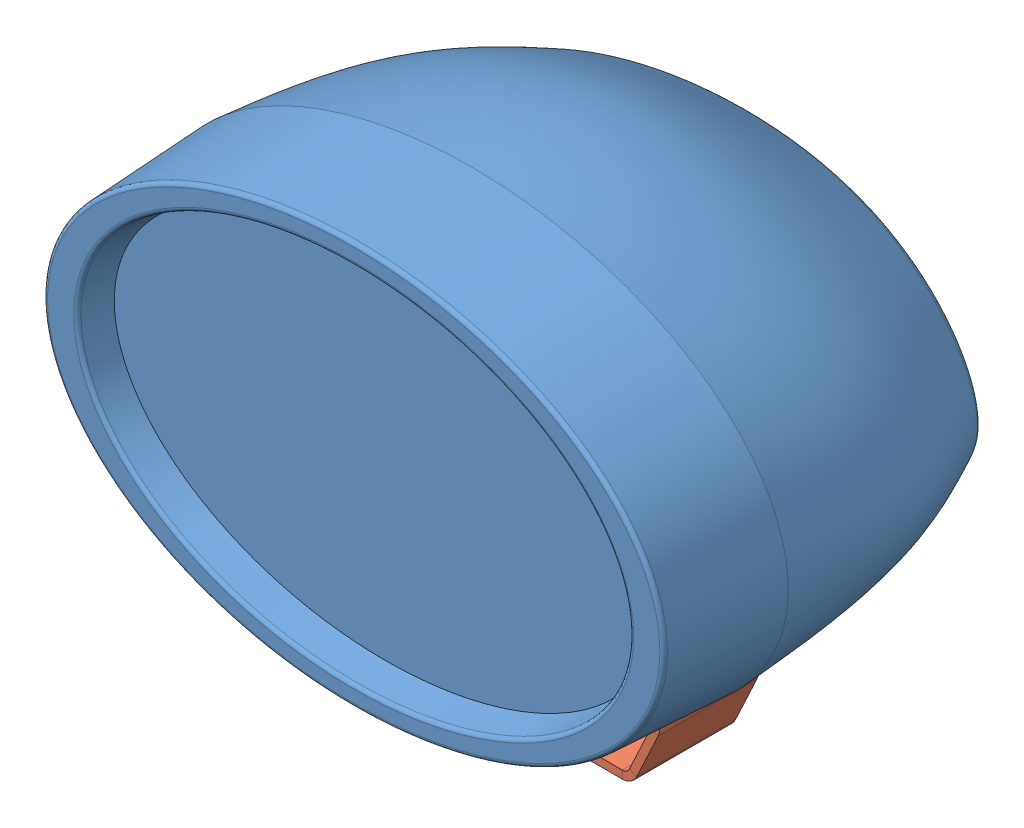
SolidWorks assembly 28308, configuration Default. Lengths in mm.
Overall size (166.54 142.84 108.36).
2 component instances, 2 part files, 3 mates.
Components (placement in the parent):
- 28308-1: 28308 [Default] at origin size (166.54 125.72 108.36)
- 28308_beslag-1: 28308_beslag [Default] at (0 -87.1153 -37) x (1 0 0) z (0 1 0) size (45.88 25 42.62)
Mates (geometry in assembly coordinates):
- Concentric1: concentric anti-aligned: cylinder of 28308-1 through (20 -57 -37) axis (-1 0 0) radius 4.25; cylinder of 28308_beslag-1 through (20.9421 -57 -37) axis (1 0 0) radius 4.5
- Angle1: planar angle = 3.141593 rad aligned: plane of 28308_beslag-1 through (0 -87.1153 -37) normal (0 0 -1); plane of assembly through (0 0 0) normal (0 0 1)
- Coincident2: coincident aligned: plane of 28308_beslag-1 through (0 -87.1153 -37) normal (1 0 0); plane of assembly through (0 0 0) normal (1 0 0)
